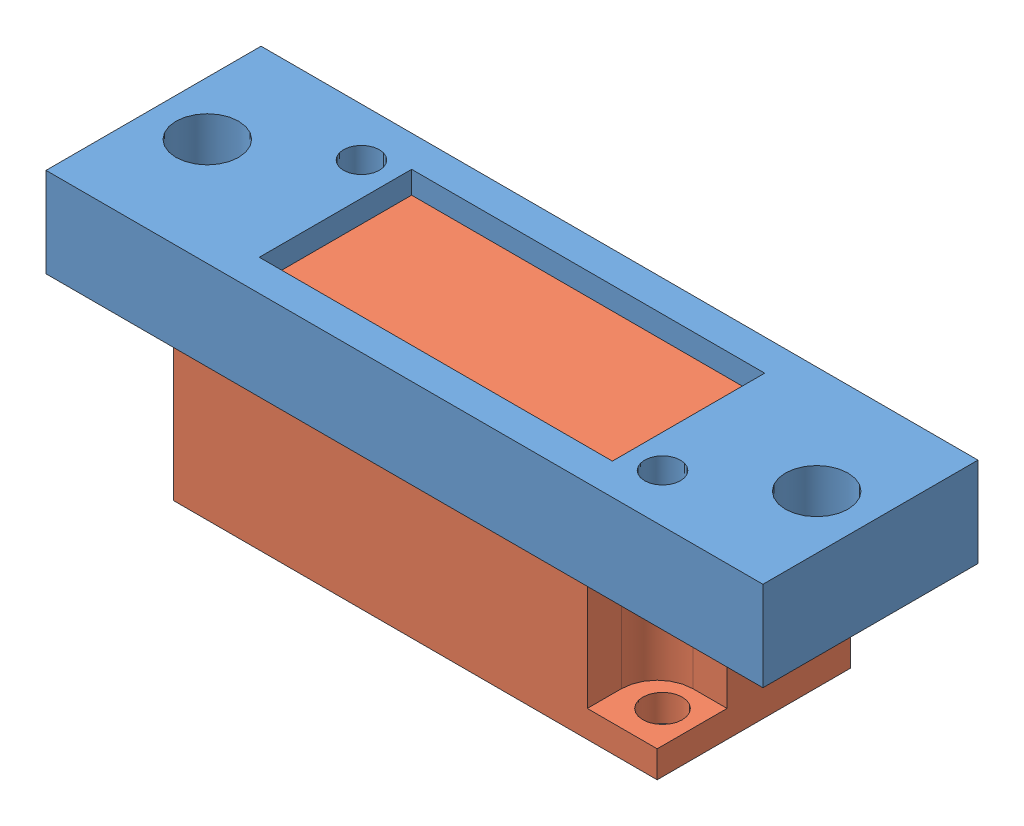
SolidWorks assembly gp2y0a51sk0f_asm, configuration Default. Lengths in mm.
Overall size (40 16 12).
2 component instances, 2 part files, 3 mates.
Components (placement in the parent):
- gp2y0a51sk0f_brk-1: gp2y0a51sk0f_brk [Default] at (16.0261 22.3452 29.1261) size (40 8 12)
- gp2y0a51sk0f_NEW-1: gp2y0a51sk0f_NEW [Default] at (16.0261 14.3452 29.1261) size (27 12 10.8)
Mates (geometry in assembly coordinates):
- 거리1: distance = 0 mm anti-aligned: plane of gp2y0a51sk0f_NEW-1 through (16.0261 22.3452 29.1261) normal (0 1 0); plane of gp2y0a51sk0f_brk-1 through (16.0261 22.3452 29.1261) normal (0 -1 0)
- 동심1: concentric aligned: cylinder of gp2y0a51sk0f_brk-1 through (27.7261 22.3452 32.4261) axis (0 1 0) radius 1; cylinder of gp2y0a51sk0f_NEW-1 through (27.7261 -14.1548 32.4261) axis (0 1 0) radius 1.1
- 동심2: concentric aligned: cylinder of gp2y0a51sk0f_brk-1 through (4.3261 22.3452 25.8261) axis (0 1 0) radius 1; cylinder of gp2y0a51sk0f_NEW-1 through (4.3261 -14.1548 25.8261) axis (0 1 0) radius 1.1
